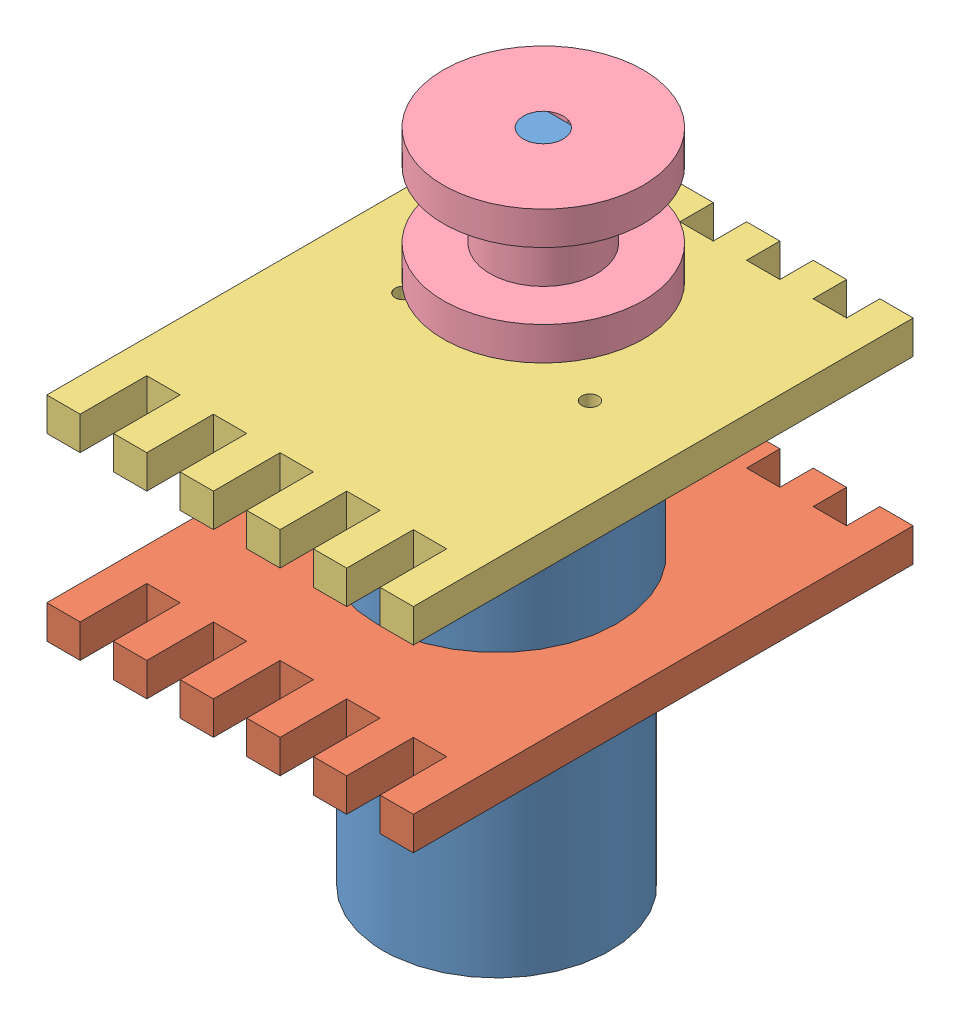
SolidWorks assembly Assemblage1, configuration Défaut. Lengths in mm.
Overall size (55 100 75).
4 component instances, 4 part files, 9 mates.
Components (placement in the parent):
- moteur_bras_peche-1: moteur_bras_peche [Défaut] at (-22.474 -39.4321 100) size (36 100 36)
- Support moteur arrière-1: Support moteur arrière [Défaut] at (5.026 3.5679 130) x (-1 0 0) z (0 -1 0) size (55 75 5)
- Support moteur avant-1: Support moteur avant [Défaut] at (5.026 30.5679 130) x (-1 0 0) z (0 -1 0) size (55 75 5)
- poulie-1: poulie [Défaut] at (-22.474 35.5679 93) x (1 0 0) z (0 1 0) size (30 30 20)
Mates (geometry in assembly coordinates):
- Coaxiale1: concentric anti-aligned: cylinder of moteur_bras_peche-1 through (-22.474 3.5679 100) axis (0 -1 0) radius 17; cylinder of Support moteur arrière-1 through (-22.474 -1.4321 100) axis (0 1 0) radius 17
- Coïncidente1: coincident anti-aligned: plane of moteur_bras_peche-1 through (-22.474 3.5679 100) normal (0 -1 0); plane of Support moteur arrière-1 through (2.2975 3.5679 132.2897) normal (0 1 0)
- Coaxiale2: concentric anti-aligned: cylinder of moteur_bras_peche-1 through (-22.474 30.5679 93) axis (0 -1 0) radius 6; cylinder of Support moteur avant-1 through (-22.474 25.5679 93) axis (0 1 0) radius 6
- Coïncidente2: coincident anti-aligned: plane of moteur_bras_peche-1 through (-22.474 25.5679 100) normal (0 1 0); plane of Support moteur avant-1 through (5.026 25.5679 130) normal (0 -1 0)
- Coaxiale3: concentric aligned: cylinder of moteur_bras_peche-1 through (-36.474 20.5679 100) axis (0 1 0) radius 1.25; cylinder of Support moteur avant-1 through (-36.474 25.5679 100) axis (0 1 0) radius 1.25
- Parallèle1: parallel aligned: plane of Support moteur arrière-1 through (5.026 -1.4321 140) normal (0 0 1); plane of Support moteur avant-1 through (5.026 25.5679 140) normal (0 0 1)
- Coïncidente4: coincident: plane of moteur_bras_peche-1 through (-22.474 65.5679 90.6) normal (0 0 -1); plane of poulie-1 through (-22.474 50.5679 90.6) normal (0 0 1)
- Coïncidente5: coincident: plane of moteur_bras_peche-1 through (-22.474 55.5679 93) normal (0 1 0); plane of poulie-1 through (-22.474 55.5679 93) normal (0 1 0)
- Coaxiale4: concentric aligned: cylinder of moteur_bras_peche-1 through (-22.474 55.5679 93) axis (0 -1 0) radius 3; cylinder of poulie-1 through (-22.474 40.5679 93) axis (0 -1 0) radius 3
